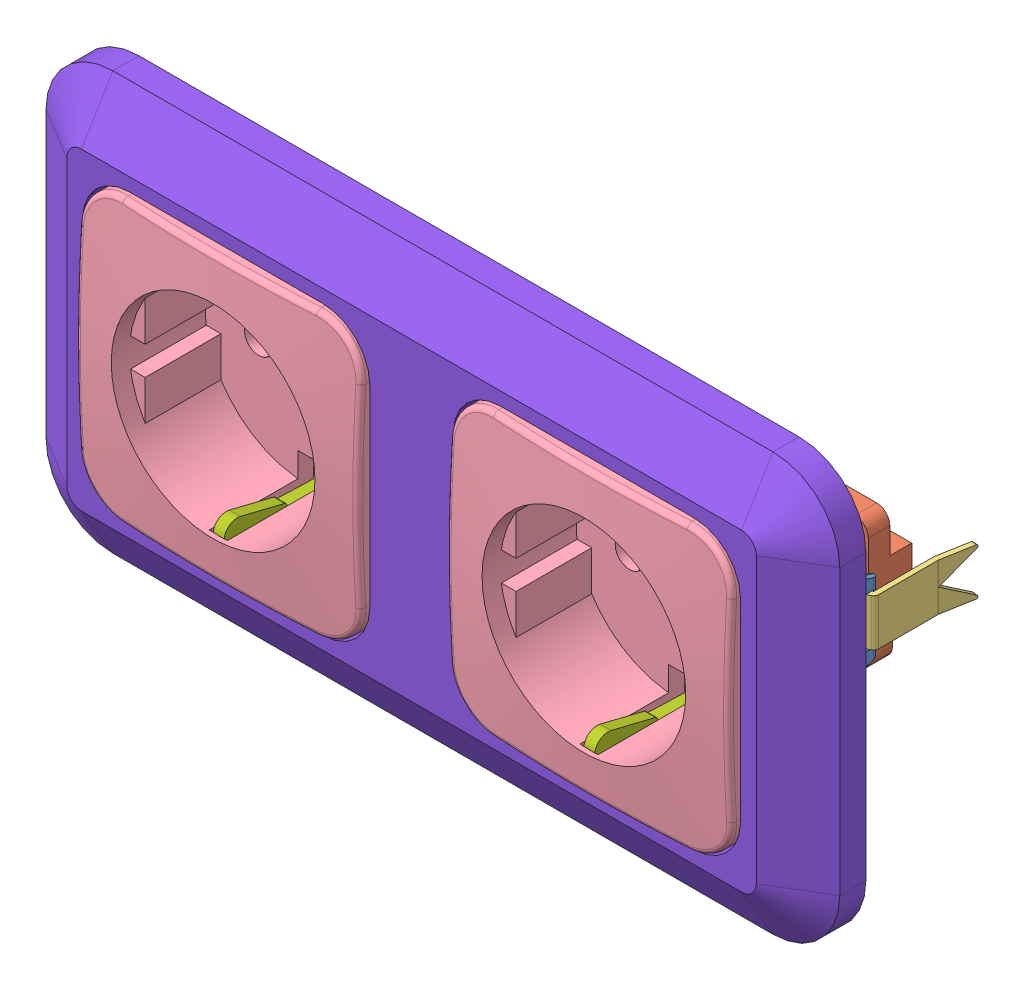
SolidWorks assembly Steckdose_2er, configuration Standard. Lengths in mm.
Overall size (152 80 49.07).
19 component instances, 8 part files, 6 mates.
Components (placement in the parent):
- Steckdose-1: Steckdose [Standard] at (57.8004 107.6649 -6.8552) x (1 0 0) z (0 -1 0) size (71 49.07 71)
  - Montageplatte.02-1: Montageplatte.02 [Standard] at (-76.9981 11 50.9191) x (1 0 0) z (0 1 0) size (71 71 18.97)
  - Halter-1: Halter [Standard] at (-76.9981 11 50.9191) x (1 0 0) z (0 1 0) size (45.97 31.9 15.37)
  - Kralle.04-1: Kralle.04 [Standard] at (-74.3121 12.4168 50.9191) x (0.996195 -0.087156 0) z (0.087156 0.996195 0) size (8.78 9 23.36)
  - Kralle.04-2: Kralle.04 [Standard] at (74.3121 12.4168 -50.9191) x (-0.996195 -0.087156 0) z (-0.087156 0.996195 0) size (8.78 9 23.36)
  - Buchse-1: Buchse [Standard] at (-76.9981 11 50.9191) x (1 0 0) z (0 1 0) size (64.03 64.03 27)
  - Stromklemme_1.02-1: Stromklemme_1.02 [Standard] at (-76.9981 11 50.7921) x (1 0 0) z (0 1 0) size (8.38 19.82 12.51)
  - Stromklemme_2.02-1: Stromklemme_2.02 [Standard] at (-76.9981 11 50.7921) x (1 0 0) z (0 1 0) size (8.38 19.82 12.51)
  - Erdleiter-1: Erdleiter [Standard] at (-76.9981 11 50.9191) x (1 0 0) z (0 1 0) size (7.24 44.01 27.12)
- Steckdose-2: Steckdose [Standard] at (128.8004 107.6649 -6.8552) x (1 0 0) z (0 -1 0) size (71 49.07 71)
  - Montageplatte.02-1: Montageplatte.02 [Standard] at (-76.9981 11 50.9191) x (1 0 0) z (0 1 0) size (71 71 18.97)
  - Halter-1: Halter [Standard] at (-76.9981 11 50.9191) x (1 0 0) z (0 1 0) size (45.97 31.9 15.37)
  - Kralle.04-1: Kralle.04 [Standard] at (-74.3121 12.4168 50.9191) x (0.996195 -0.087156 0) z (0.087156 0.996195 0) size (8.78 9 23.36)
  - Kralle.04-2: Kralle.04 [Standard] at (74.3121 12.4168 -50.9191) x (-0.996195 -0.087156 0) z (-0.087156 0.996195 0) size (8.78 9 23.36)
  - Buchse-1: Buchse [Standard] at (-76.9981 11 50.9191) x (1 0 0) z (0 1 0) size (64.03 64.03 27)
  - Stromklemme_1.02-1: Stromklemme_1.02 [Standard] at (-76.9981 11 50.7921) x (1 0 0) z (0 1 0) size (8.38 19.82 12.51)
  - Stromklemme_2.02-1: Stromklemme_2.02 [Standard] at (-76.9981 11 50.7921) x (1 0 0) z (0 1 0) size (8.38 19.82 12.51)
  - Erdleiter-1: Erdleiter [Standard] at (-76.9981 11 50.9191) x (1 0 0) z (0 1 0) size (7.24 44.01 27.12)
- Wandplatte-1: Wandplatte [2er] at (17.3004 67.6649 4.1448) size (152 80 11)
Mates (geometry in assembly coordinates):
- Deckungsgleich1: coincident anti-aligned: plane of Steckdose-2/Buchse-1 through (128.8004 81.1649 -1.8552) normal (0 0 -1); plane of Wandplatte-1
- Deckungsgleich2: coincident: plane of Steckdose-1/Buchse-1; plane of Wandplatte-1
- Abstand1: distance = 0.5 mm: plane of Wandplatte-1 through (39.3004 135.1649 -1.8552) normal (0 -1 0); plane of Steckdose-1/Buchse-1 through (39.3004 134.6649 -1.8552) normal (0 1 0)
- Abstand2: distance = 0.5 mm: plane of Steckdose-1/Buchse-1 through (30.8004 89.1649 -1.8552) normal (-1 0 0); plane of Wandplatte-1 through (30.3004 126.1649 -1.8552) normal (1 0 0)
- Abstand3: distance = 0.5 mm anti-aligned: plane of Steckdose-2/Buchse-1 through (110.3004 134.6649 -1.8552) normal (0 1 0); plane of Wandplatte-1 through (110.3004 135.1649 -1.8552) normal (0 -1 0)
- Abstand4: distance = 0.5 mm anti-aligned: plane of Steckdose-2/Buchse-1 through (101.8004 89.1649 -1.8552) normal (-1 0 0); plane of Wandplatte-1 through (101.3004 126.1649 -1.8552) normal (1 0 0)
